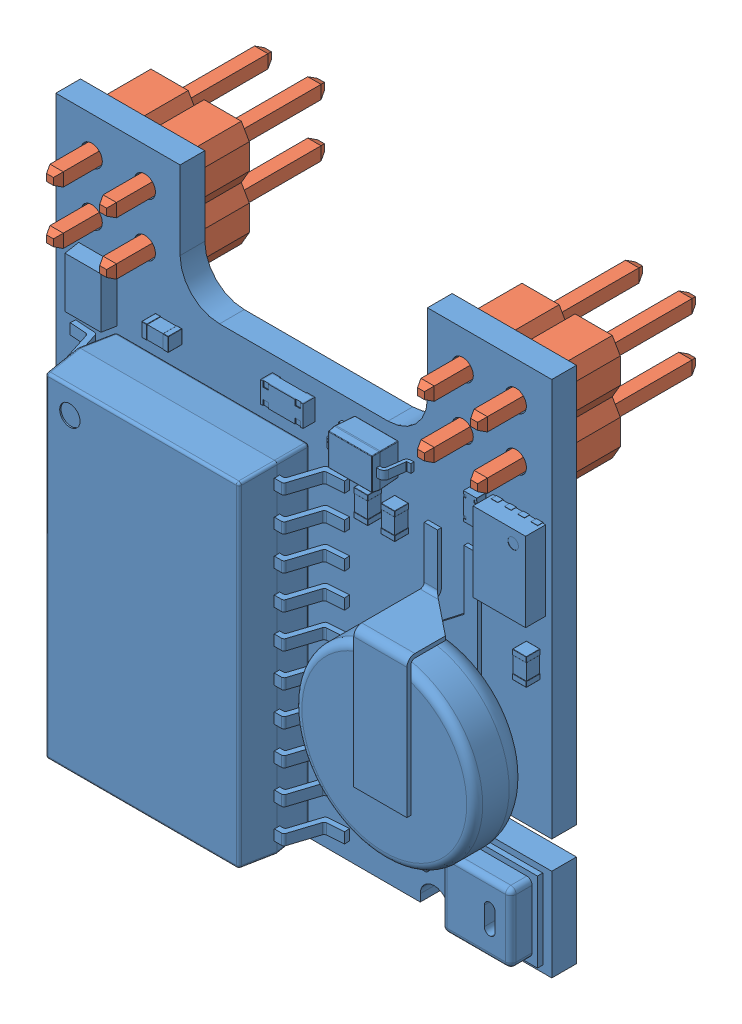
SolidWorks assembly SAU-G0-EX_AHT-PL_PCB, configuration 默认. Lengths in mm.
Overall size (18.66 19.5 9.43).
3 component instances, 2 part files, 7 mates.
Components (placement in the parent):
- SAU-G0-EX_AHT-PL_STEP_AD-1: SAU-G0-EX_AHT-PL_STEP_AD [默认] at (23.688 -2.438 0) x (-1 0 0) z (0 0 -1) size (18.66 19.5 3.73)
- 2.0mm排针2x2-1: 2.0mm排针2x2 [Default] at (-1.352 18.152 0) x (1 0 0) z (0 1 0) size (4 8.2 4)
- 2.0mm排针2x2-2: 2.0mm排针2x2 [Default] at (-17.312 16.152 0) x (-1 0 0) z (0 -1 0) size (4 8.2 4)
Mates (geometry in assembly coordinates):
- 重合1: coincident anti-aligned: plane of SAU-G0-EX_AHT-PL_STEP_AD-1 through (-16.6577 9.2215 0) normal (0 0 -1); plane of 2.0mm排针2x2-1 through (-9.4122 18.152 0) normal (0 0 1)
- 平行1: parallel aligned: plane of SAU-G0-EX_AHT-PL_STEP_AD-1 through (-12.7382 19.504 0.9297) normal (0 1 0); plane of 2.0mm排针2x2-1 through (-10.4122 19.152 -2) normal (0 1 0)
- 距离1: distance = 0.25 mm: plane of 2.0mm排针2x2-1 through (-3.102 18.402 2.5) normal (0 1 0); cylinder of SAU-G0-EX_AHT-PL_STEP_AD-1 through (-3.352 18.152 0.9297) axis (0 0 1) radius 0.4
- 距离2: distance = 0.25 mm: plane of 2.0mm排针2x2-1 through (-3.602 18.402 2.5) normal (-1 0 0); cylinder of SAU-G0-EX_AHT-PL_STEP_AD-1 through (-3.352 18.152 0.9297) axis (0 0 1) radius 0.4
- 重合2: coincident anti-aligned: plane of SAU-G0-EX_AHT-PL_STEP_AD-1 through (-8.5975 9.2215 0) normal (0 0 -1); plane of assembly through (0 0 0) normal (0 0 1)
- 重合3: coincident anti-aligned: plane of SAU-G0-EX_AHT-PL_STEP_AD-1 through (-4.948 0 0.9297) normal (0 -1 0); plane of assembly
- 重合5: coincident aligned: plane of SAU-G0-EX_AHT-PL_STEP_AD-1 through (0 19.504 0.9297) normal (1 0 0); plane of assembly
